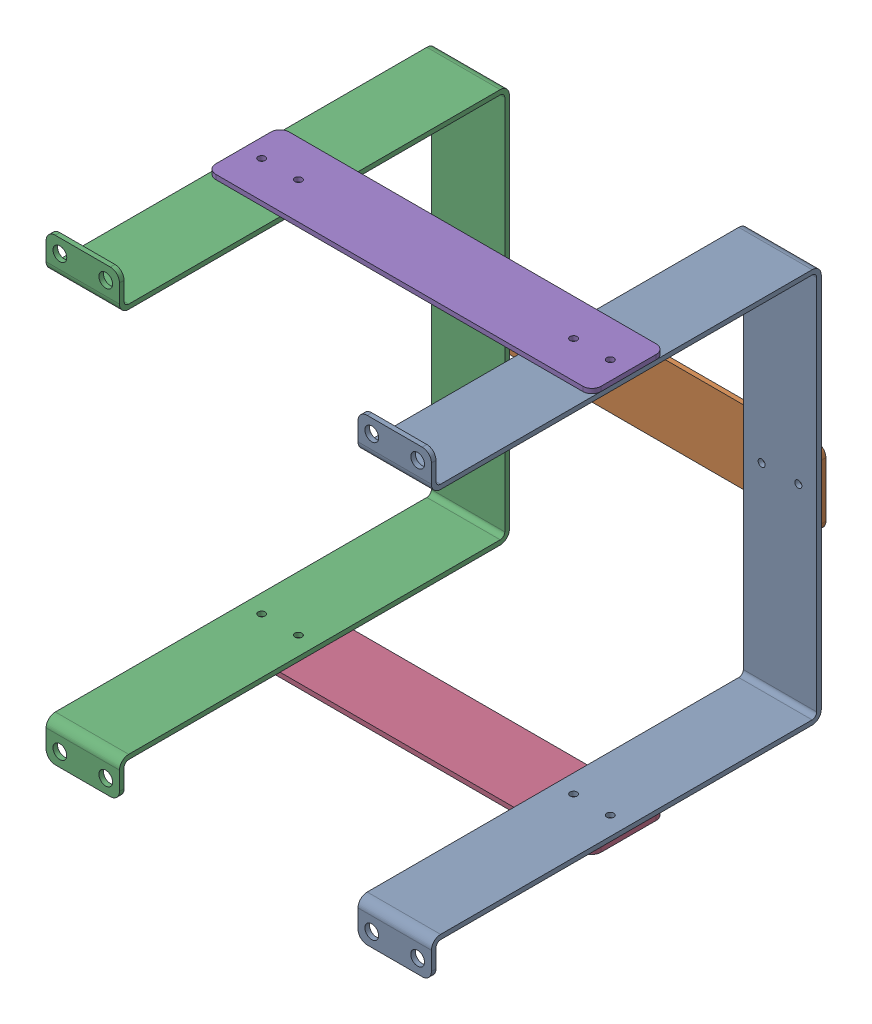
SolidWorks assembly GE-16121_ASM, configuration Default. Lengths in mm.
Overall size (266.7 317.5 273.06).
5 component instances, 2 part files, 0 mates.
Components (placement in the parent):
- GE-16122-1: GE-16122 [Default] at origin size (50.8 317.5 269.88)
- GE-16123-1: GE-16123 [Default] at (-82.55 0 0) x (0 1 0) z (1 0 0) size (50.8 3.18 266.7)
- GE-16122-2: GE-16122 [Default] at (-215.9 0 0) size (50.8 317.5 269.88)
- GE-16123-2: GE-16123 [Default] at (-82.55 -136.525 133.35) x (0 0 -1) z (1 0 0) size (50.8 3.18 266.7)
- GE-16123-3: GE-16123 [Default] at (-82.55 136.525 133.35) x (0 0 1) z (1 0 0) size (50.8 3.18 266.7)
